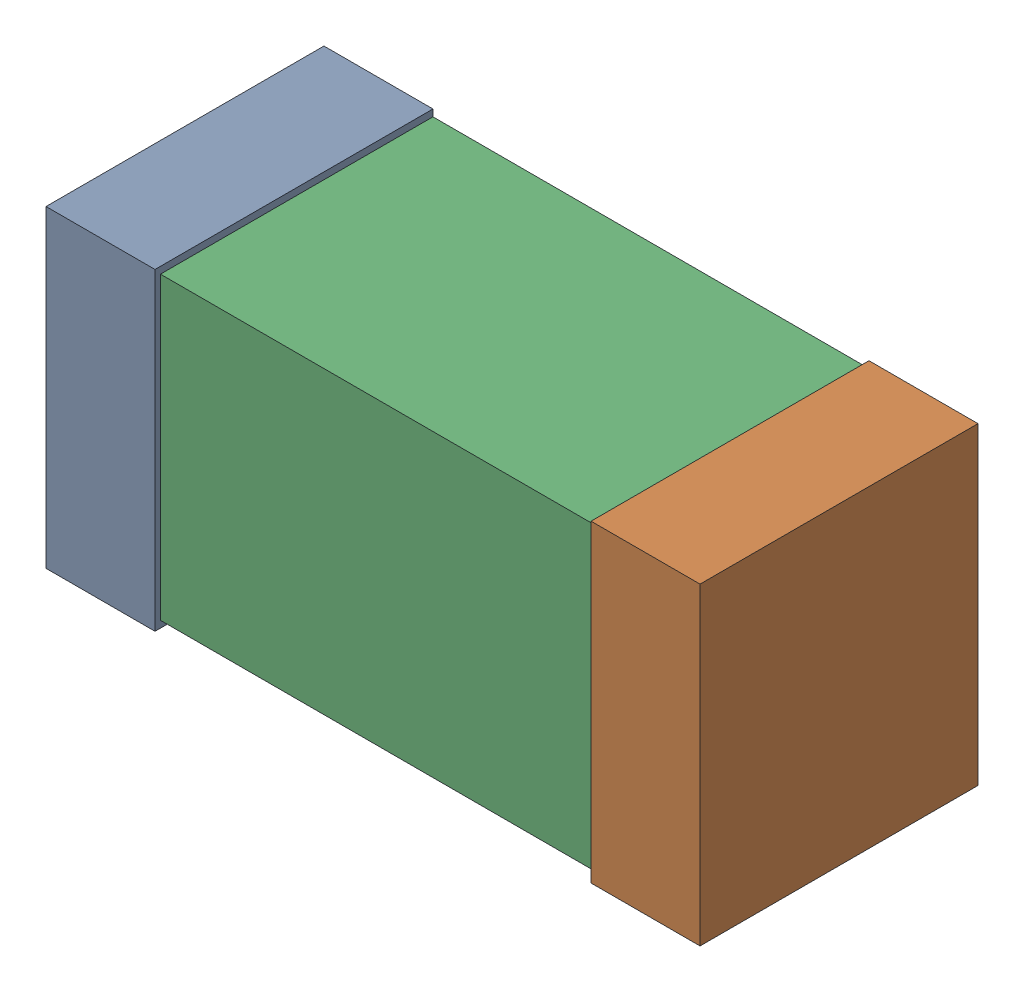
SolidWorks assembly .1uFKanaloa_v2.0.0_Power_1, configuration Default. Lengths in mm.
Overall size (1.2 0.58 0.51).
6 component instances, 2 part files, 0 mates.
Components (placement in the parent):
- 378153536-1: 378153536 [Default] at (142.8968 96.4164 0) size (0.2 0.58 0.51)
  - Extruded_19-1: Extruded_19 [Default] at origin size (0.2 0.58 0.51)
- 378153536-2: 378153536 [Default] at (143.8968 96.4164 0) size (0.2 0.58 0.51)
  - Extruded_19-1: Extruded_19 [Default] at origin size (0.2 0.58 0.51)
- 378153664-1: 378153664 [Default] at (143.3968 96.4164 0) size (1.15 0.55 0.5)
  - Extruded_20-1: Extruded_20 [Default] at origin size (1.15 0.55 0.5)
